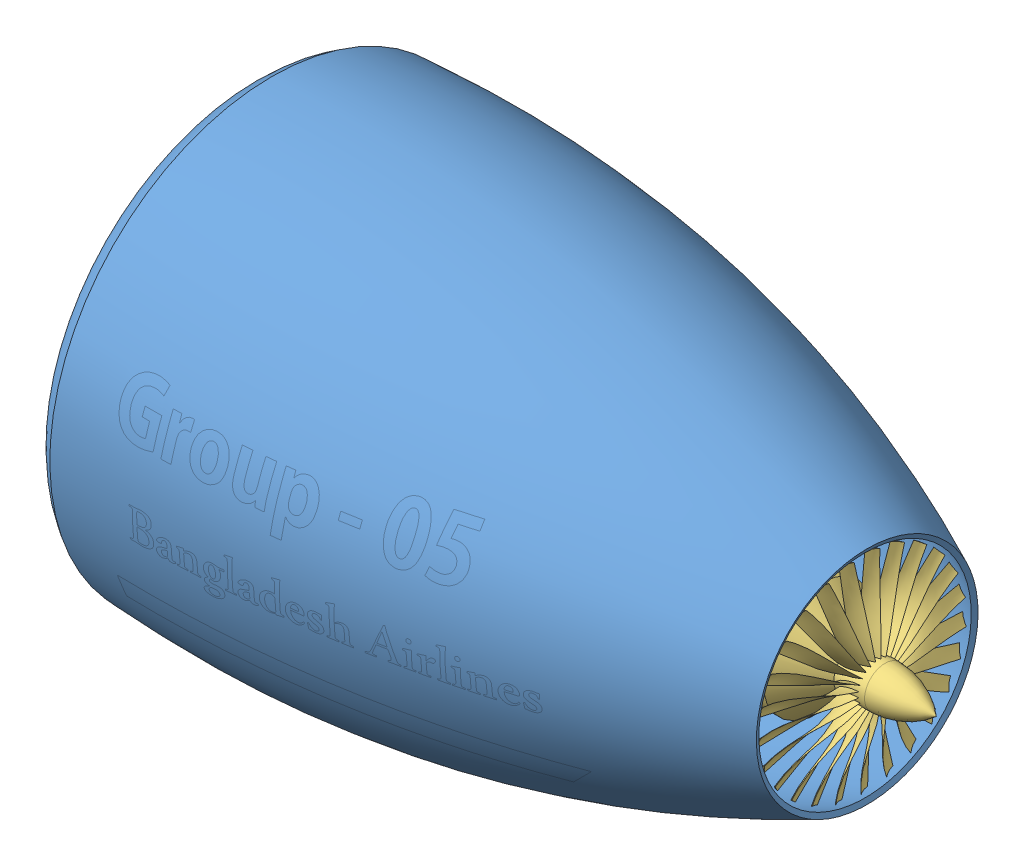
SolidWorks assembly Propeller Jet Engine, configuration Default. Lengths in mm.
Overall size (962 456.95 457.56).
3 component instances, 3 part files, 6 mates.
Components (placement in the parent):
- 3. housing-1: 3. housing [Default] at (68.1618 344.6624 371.2708) size (598.54 453.63 453.63)
- 1. propeller-1: 1. propeller [Default] at (-62.4712 344.6624 371.2708) x (0 0.911321 -0.411696) z (-1 0 0) size (345 346.23 352.96)
- 2.Shaft-1: 2.Shaft [Default] at (65.5288 344.6624 371.2708) x (1 0 0) z (0 -0.911321 0.411696) size (650 199.98 200.27)
Mates (geometry in assembly coordinates):
- Concentric1: concentric aligned: cylinder of 1. propeller-1 through (65.5288 344.6624 371.2708) axis (1 0 0) radius 20; cylinder of 2.Shaft-1 through (665.5288 344.6624 371.2708) axis (1 0 0) radius 20
- Concentric2: concentric aligned: cylinder of 1. propeller-1 through (65.5288 344.6624 371.2708) axis (1 0 0) radius 20; cylinder of 2.Shaft-1 through (665.5288 344.6624 371.2708) axis (1 0 0) radius 20
- Coincident1: coincident anti-aligned: plane of 1. propeller-1 through (65.5288 344.6624 371.2708) normal (1 0 0); plane of 2.Shaft-1 through (65.5288 344.6624 371.2708) normal (-1 0 0)
- Concentric3: concentric anti-aligned: cylinder of 3. housing-1 through (696.5385 344.6624 371.2708) axis (-1 0 0) radius 190; cylinder of 2.Shaft-1 through (665.5288 344.6624 371.2708) axis (1 0 0) radius 48.085
- Distance1: distance = 40 mm anti-aligned: plane of 2.Shaft-1 through (165.5288 352.8964 389.4972) normal (-1 0 0); plane of 3. housing-1 through (125.5288 344.6624 371.2708) normal (1 0 0)
- Coincident3: coincident anti-aligned: plane of 1. propeller-1 through (-62.4712 344.6624 371.2708) normal (0 -0.411696 -0.911321); plane of 2.Shaft-1 through (65.5288 344.6624 371.2708) normal (0 0.411696 0.911321)
